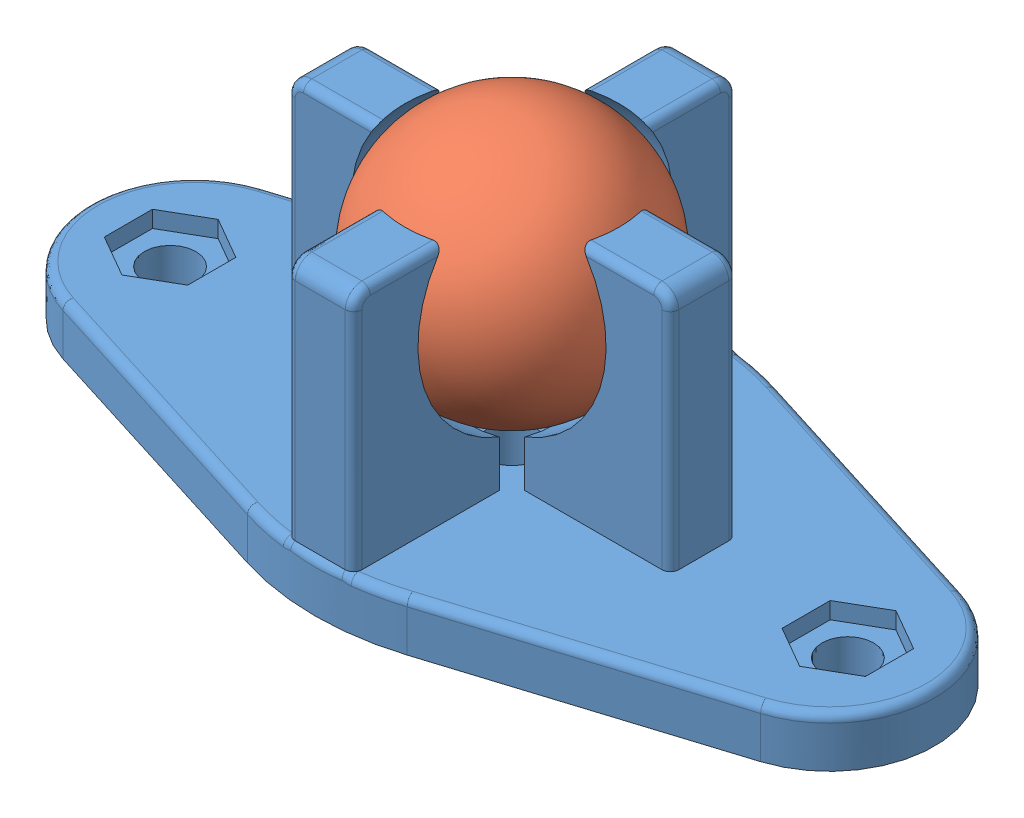
SolidWorks assembly Scroller, configuration Default. Lengths in mm.
Overall size (50.67 20.4 23.62).
2 component instances, 2 part files, 2 mates.
Components (placement in the parent):
- Scroller Stand-1: Scroller Stand [Default] at (18.2421 19.7342 46.6095) x (1 0 0) z (0 1 0) size (50.67 23.62 17.5)
- Ball-1: Ball [Default] at (18.2421 32.6342 46.6095) size (15 15 15)
Mates (geometry in assembly coordinates):
- Concentric2: concentric anti-aligned: circle of support plastique-1; circle of ball-1
- Coincident1: coincident anti-aligned: line of support plastique-1 through (18.2421 24.7342 46.6095) axis (0 1 0); line of ball-1 through (18.2421 40.1342 46.6095) axis (0 -1 0)
